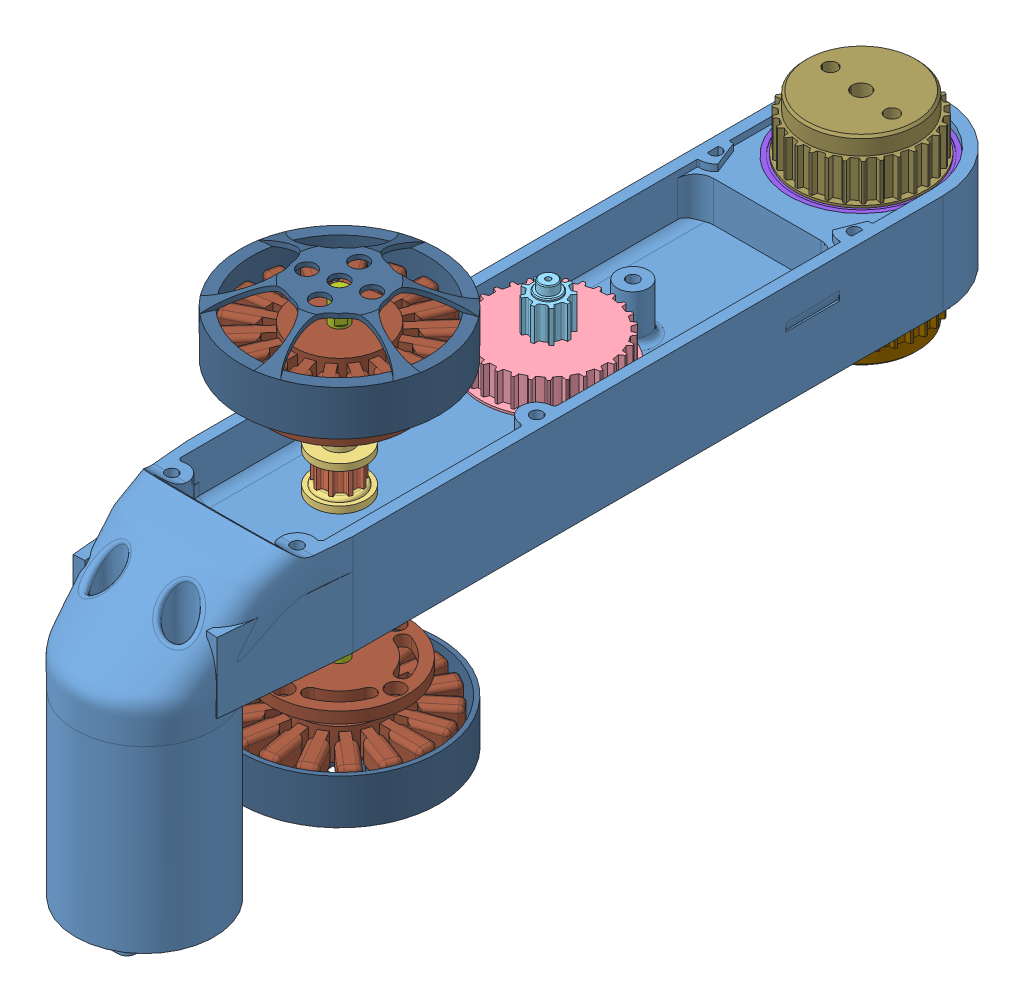
SolidWorks assembly act_core_v3_only body, configuration Default. Lengths in mm.
Overall size (62.68 103.74 194.04).
24 component instances, 12 part files, 56 mates.
Components (placement in the parent):
- upper leg module shell base_v3-1: upper leg module shell base_v3 [Default] at (27.0686 103.6753 170.704) x (-1 0 0) z (0 0 -1) size (37.45 78.01 194.01)
- motor assembly-1: motor assembly [Default] at (27.0686 129.5753 226.2245) x (0.534678 0 -0.845056) z (0.845056 0 0.534678) size (16.67 11.86 16.67)
  - motor pulley-1: motor pulley [Default] at (0 -20.1 0) x (1 0 0) z (0 -1 0) size (8.98 9.1 6.7)
  - encoder wheel mount-1: encoder wheel mount [Default] at (0 -28.3 0) x (-0.562764 0 0.826618) z (-0.826618 0 -0.562764) size (12 5.96 12) (hidden)
- centre pulley-1: centre pulley [Default] at (39.24 91.3287 156.2358) x (0.712464 0 0.701709) z (-0.701709 0 0.712464) size (30 19 30)
  - transmission pulley centre-1: transmission pulley centre [Default] at (7.726 11.8465 25.1899) size (30 6.8 30)
  - centre pulley-1: centre pulley [Default] at (7.726 25.3465 25.1899) x (0.694658 0 -0.71934) z (0 -1 0) size (8.98 9.1 19)
- bearing 8mm x 3mm x 3mm-1: bearing 8mm x 3mm x 3mm [Default] at (27.0686 102.1753 179.604) x (0.990426 0 -0.138045) z (0 -1 0) size (7.96 7.96 3)
- motor shaft_v3-1: motor shaft_v3 [Default] at (27.0686 140.6753 226.2245) x (0.606053 0 -0.795424) z (0 -1 0) size (3.99 3.99 38)
- encoder wheel mount-1: encoder wheel mount [Default] at (27.0686 110.9753 226.2245) x (1 0 0) z (0 0 -1) size (12 5.96 12)
- bearing 32x25x4mm-1: bearing 32x25x4mm [Default] at (27.0686 104.1753 109.704) x (0.998143 0 0.060919) z (-0.060919 0 0.998143) size (32 4 32)
- centre pulley-2: centre pulley [Default] at (27.0686 93.6753 179.604) x (-0.512258 0 -0.858832) z (0 -1 0) size (8.98 9.1 19)
- transmission pulley centre-1: transmission pulley centre [Default] at (27.0686 93.1753 179.604) x (0.289271 0 0.957247) z (0.957247 0 -0.289271) size (30 6.8 30)
- motor pulley-1: motor pulley [Default] at (27.0686 93.6753 226.2245) x (0.534678 0 -0.845056) z (0 -1 0) size (8.98 9.1 6.7)
- encoder wheel mount-2: encoder wheel mount [Default] at (27.0686 84.6753 226.2245) x (0.036347 0 0.999339) z (-0.999339 0 0.036347) size (12 5.96 12)
- transmission pulley output-2: transmission pulley output [Default] at (27.0686 88.1753 109.704) x (0.336451 0 0.941701) z (0.941701 0 -0.336451) size (29 16.4 29)
- motor stator-1: motor stator [Default] at (27.0686 61.9826 226.2245) x (0.681591 0 0.731733) z (0 -1 0) size (44.35 44.35 16.24)
- motor rotor-1: motor rotor [Default] at (27.0686 61.9826 226.2245) x (1 0 0) z (0 0 -1) size (40 13.5 39.72)
- bearing 32x25x4mm-2: bearing 32x25x4mm [Default] at (27.0686 88.6753 109.704) x (0.98877 0 0.149448) z (-0.149448 0 0.98877) size (32 4 32)
- bearing 8mm x 3mm x 3mm-3: bearing 8mm x 3mm x 3mm [Default] at (27.0686 97.1753 179.604) x (0.918615 0 -0.395154) z (0 -1 0) size (7.96 7.96 3)
- motor shaft_v3-2: motor shaft_v3 [Default] at (27.0686 55.6753 226.2245) x (1 0 0) z (0 1 0) size (3.99 3.99 38)
- transmission pulley output_wheel-1: transmission pulley output_wheel [Default] at (27.0686 108.6753 109.704) x (0.991072 0 0.133328) z (-0.133328 0 0.991072) size (29 16.4 29)
- motor stator-2: motor stator [Default] at (27.0686 127.1753 226.2245) x (-0.970824 0 0.239792) z (0 1 0) size (44.35 44.35 16.24)
- motor rotor-2: motor rotor [Default] at (27.0686 128.1753 226.2245) x (-0.84562 0 -0.533785) z (0.533785 0 -0.84562) size (40 13.5 39.72)
Mates (geometry in assembly coordinates):
- Coincident1: coincident aligned: plane of upper leg module shell base_v3-1 through (45.5686 97.6753 130.704) normal (1 0 0); plane of upper leg module cover_v2_2-1 through (45.5686 117.6753 241.7032) normal (1 0 0)
- Coincident2: coincident anti-aligned: plane of upper leg module shell base_v3-1 through (8.5686 109.6753 130.704) normal (0 1 0); plane of upper leg module cover_v2_2-1 through (27.0686 109.6753 164.3332) normal (0 -1 0)
- Concentric1: concentric aligned: cylinder of upper leg module shell base_v3-1 through (27.0686 96.8953 109.704) axis (0 -1 0) radius 18.5018; cylinder of upper leg module cover_v2_2-1 through (27.0686 125.6853 109.704) axis (0 -1 0) radius 18.5018
- Coincident3: coincident anti-aligned: plane of upper leg module shell base_v3-1 through (27.0686 87.1753 109.704) normal (0 -1 0); plane of upper leg module cover_v2_2-2 through (27.0686 87.1753 164.3332) normal (0 1 0)
- Coincident5: coincident aligned: plane of upper leg module shell base_v3-1 through (45.5686 97.6753 130.704) normal (1 0 0); plane of upper leg module cover_v2_2-2 through (45.5686 79.1753 241.7032) normal (1 0 0)
- Concentric6: concentric anti-aligned: cylinder of upper leg module shell base_v3-1 through (27.0686 101.1753 179.604) axis (0 -1 0) radius 3.98; cylinder of centre pulley-1/centre pulley-1 through (27.0686 100.1753 179.604) axis (0 1 0) radius 1.995
- Concentric7: concentric anti-aligned: cylinder of upper leg module shell base_v3-1 through (27.0686 101.1753 179.604) axis (0 -1 0) radius 3.98; cylinder of bearing 8mm x 3mm x 3mm-1 through (27.0686 99.1753 179.604) axis (0 1 0) radius 3.98
- Coincident12: coincident anti-aligned: plane of upper leg module shell base_v3-1 through (13.5686 99.1753 130.704) normal (0 1 0); plane of bearing 8mm x 3mm x 3mm-1 through (27.0686 99.1753 179.604) normal (0 -1 0)
- Coincident15: coincident anti-aligned: plane of centre pulley-1/centre pulley-1 through (27.0686 102.1753 179.604) normal (0 -1 0); plane of bearing 8mm x 3mm x 3mm-1 through (27.0686 102.1753 179.604) normal (0 1 0)
- Coincident16: coincident aligned: plane of motor assembly-1/motor pulley-1 through (27.0686 109.4753 226.2245) normal (0 1 0); plane of centre pulley-1/transmission pulley centre-1 through (27.0686 109.4753 179.604) normal (0 1 0)
- Coincident17: coincident aligned: plane of centre pulley-1/transmission pulley centre-1 through (27.0686 102.6753 179.604) normal (0 -1 0); plane of motor shaft_v3-1 through (27.0686 102.6753 226.2245) normal (0 -1 0)
- Concentric9: concentric aligned: cylinder of motor assembly-1/motor pulley-1 through (27.0686 102.7753 226.2245) axis (0 1 0) radius 2; cylinder of motor shaft_v3-1 through (27.0686 102.6753 226.2245) axis (0 1 0) radius 1.995
- Parallel1: parallel aligned: plane of motor assembly-1/motor pulley-1 through (27.0686 102.7753 226.2245) normal (0 -1 0); plane of motor shaft_v3-1 through (27.0686 102.6753 226.2245) normal (0 -1 0)
- Concentric10: concentric aligned: cylinder of motor shaft_v3-1 through (27.0686 102.6753 226.2245) axis (0 1 0) radius 1.995; cylinder of encoder wheel mount-1 through (27.0686 106.9753 226.2245) axis (0 1 0) radius 2
- Coincident19: coincident anti-aligned: plane of motor assembly-1/motor pulley-1 through (27.0686 109.4753 226.2245) normal (0 1 0); plane of encoder wheel mount-1 through (27.0686 109.4753 226.2245) normal (0 -1 0)
- Concentric11: concentric anti-aligned: cylinder of upper leg module shell base_v3-1 through (27.0686 104.1753 109.704) axis (0 1 0) radius 16; cylinder of bearing 32x25x4mm-1 through (27.0686 108.1753 109.704) axis (0 -1 0) radius 12.5
- Coincident20: coincident anti-aligned: plane of upper leg module shell base_v3-1 through (27.0686 104.1753 109.704) normal (0 1 0); plane of bearing 32x25x4mm-1 through (27.0686 104.1753 109.704) normal (0 -1 0)
- Concentric12: concentric anti-aligned: cylinder of bearing 32x25x4mm-1 through (27.0686 108.1753 109.704) axis (0 -1 0) radius 12.5; cylinder of transmission pulley output-1 through (27.0686 104.3253 109.704) axis (0 1 0) radius 12.575
- Coincident21: coincident anti-aligned: plane of bearing 32x25x4mm-1 through (27.0686 108.1753 109.704) normal (0 1 0); plane of transmission pulley output-1 through (27.0686 108.1753 109.704) normal (0 -1 0)
- Concentric14: concentric anti-aligned: cylinder of upper leg module shell base_v3-1 through (27.0686 88.8753 109.704) axis (0 1 0) radius 16.5; cylinder of bearing 32x25x4mm-2 through (27.0686 92.6753 109.704) axis (0 -1 0) radius 16
- Coincident22: coincident anti-aligned: plane of upper leg module shell base_v3-1 through (27.0686 92.6753 109.704) normal (0 -1 0); circle of bearing 32x25x4mm-2
- Concentric16: concentric aligned: cylinder of transmission pulley output-2 through (27.0686 92.5253 109.704) axis (0 -1 0) radius 12.575; cylinder of bearing 32x25x4mm-2 through (27.0686 92.6753 109.704) axis (0 -1 0) radius 12.5
- Coincident23: coincident anti-aligned: plane of transmission pulley output-2 through (27.0686 88.6753 109.704) normal (0 1 0); plane of bearing 32x25x4mm-2 through (27.0686 88.6753 109.704) normal (0 -1 0)
- Concentric17: concentric aligned: cylinder of upper leg module shell base_v3-1 through (27.0686 96.1753 179.604) axis (0 1 0) radius 3.98; cylinder of bearing 8mm x 3mm x 3mm-3 through (27.0686 94.1753 179.604) axis (0 1 0) radius 3.98
- Coincident25: coincident anti-aligned: plane of upper leg module shell base_v3-1 through (27.0686 97.1753 179.604) normal (0 -1 0); plane of bearing 8mm x 3mm x 3mm-3 through (27.0686 97.1753 179.604) normal (0 1 0)
- Concentric18: concentric anti-aligned: cylinder of centre pulley-2 through (27.0686 96.1753 179.604) axis (0 -1 0) radius 1.995; cylinder of bearing 8mm x 3mm x 3mm-3 through (27.0686 94.1753 179.604) axis (0 1 0) radius 2
- Coincident26: coincident anti-aligned: plane of centre pulley-2 through (27.0686 94.1753 179.604) normal (0 1 0); plane of bearing 8mm x 3mm x 3mm-3 through (27.0686 94.1753 179.604) normal (0 -1 0)
- Coincident27: coincident aligned: plane of centre pulley-2 through (27.0686 93.6753 179.604) normal (0 1 0); plane of transmission pulley centre-1 through (27.0686 93.6753 179.604) normal (0 1 0)
- Concentric19: concentric aligned: circle of centre pulley-2; cylinder of transmission pulley centre-1 through (27.0686 93.6753 179.604) axis (0 -1 0) radius 15
- Coincident28: coincident aligned: cylinder of centre pulley-2 through (27.0686 79.6753 179.604) axis (0 1 0) radius 4.57; circle of transmission pulley centre-1
- Parallel2: parallel anti-aligned: plane of transmission pulley centre-1 through (27.2454 96.8753 175.7377) normal (0.969507 0 0.245065); plane of centre pulley-2 through (26.3162 79.6753 179.4139) normal (-0.969507 0 -0.245065)
- Coincident30: coincident anti-aligned: plane of upper leg module cover_v2_2-2 through (27.0686 79.1753 164.3332) normal (0 -1 0); plane of motor rotor-1 through (27.0686 69.4826 226.2245) normal (0 1 0)
- Concentric20: concentric aligned: cylinder of upper leg module cover_v2_2-2 through (14.5686 84.1753 223.504) axis (0 -1 0) radius 1.6; cylinder of motor rotor-1 through (14.5686 69.4826 226.2245) axis (0 -1 0) radius 2
- Concentric21: concentric aligned: line of motor stator-1 through (27.0686 51.9826 226.2245) axis (0 1 0); axis of motor rotor-1 through (27.0686 55.9826 226.2245) axis (0 1 0)
- Concentric22: concentric aligned: cylinder of upper leg module cover_v2_2-2 through (27.0686 84.1753 223.504) axis (0 -1 0) radius 12.5; cylinder of motor rotor-1 through (27.0686 69.4826 226.2245) axis (0 -1 0) radius 15
- Coincident33: coincident aligned: plane of motor stator-1 through (27.0686 61.9826 226.2245) normal (0 1 0); plane of motor rotor-1 through (27.0686 61.9826 226.2245) normal (0 1 0)
- Concentric23: concentric anti-aligned: cylinder of motor rotor-1 through (27.0686 56.9826 226.2245) axis (0 1 0) radius 2; cylinder of motor shaft_v3-2 through (27.0686 93.6753 226.2245) axis (0 -1 0) radius 1.995
- Coincident34: coincident aligned: plane of transmission pulley centre-1 through (27.0686 93.6753 179.604) normal (0 1 0); plane of motor shaft_v3-2 through (27.0686 93.6753 226.2245) normal (0 1 0)
- Concentric24: concentric anti-aligned: cylinder of motor pulley-1 through (27.0686 86.9753 226.2245) axis (0 1 0) radius 2; line of motor shaft_v3-2 through (27.0686 93.4753 226.2245) axis (0 -1 0)
- Coincident35: coincident aligned: plane of transmission pulley centre-1 through (27.0686 93.6753 179.604) normal (0 1 0); plane of motor pulley-1 through (27.0686 93.6753 226.2245) normal (0 1 0)
- Concentric25: concentric aligned: line of upper leg module cover_v2_2-2 through (27.0686 83.1753 223.504) axis (0 -1 0); cylinder of encoder wheel mount-2 through (27.0686 88.6753 223.504) axis (0 -1 0) radius 2
- Coincident36: coincident anti-aligned: plane of motor pulley-1 through (27.0686 86.9753 226.2245) normal (0 -1 0); plane of encoder wheel mount-2 through (27.0686 86.9753 226.2245) normal (0 1 0)
- Concentric26: concentric anti-aligned: cylinder of bearing 32x25x4mm-1 through (27.0686 108.1753 109.704) axis (0 -1 0) radius 12.5; cylinder of transmission pulley output_wheel-1 through (27.0686 104.3253 109.704) axis (0 1 0) radius 12.575
- Coincident37: coincident anti-aligned: plane of bearing 32x25x4mm-1 through (27.0686 108.1753 109.704) normal (0 1 0); plane of transmission pulley output_wheel-1 through (27.0686 108.1753 109.704) normal (0 -1 0)
- Concentric27: concentric aligned: cylinder of motor shaft_v3-3 through (27.0686 153.0074 109.704) axis (0 -1 0) radius 1.995; cylinder of transmission pulley output_wheel-1 through (27.0686 143.4713 109.704) axis (0 -1 0) radius 1.995
- Coincident38: coincident anti-aligned: plane of transmission pulley output-2 through (37.2261 92.5253 111.3845) normal (-0.336451 0 -0.941701); plane of lower leg-1 through (21.6881 81.1653 116.9359) normal (0.336451 0 0.941701)
- Coincident39: coincident anti-aligned: plane of transmission pulley output-2 through (20.2755 92.5253 117.4406) normal (0.941701 0 -0.336451); plane of lower leg-1 through (19.7708 81.1653 116.0281) normal (-0.941701 0 0.336451)
- Coincident40: coincident anti-aligned: plane of upper leg module cover_v2_2-2 through (27.0686 71.1653 109.704) normal (0 -1 0); plane of lower leg-1 through (167.4344 71.1653 71.2351) normal (0 1 0)
- Concentric29: concentric anti-aligned: line of motor shaft_v3-1 through (27.0686 102.8753 226.2245) axis (0 1 0); cylinder of motor shaft_v3-2 through (27.0686 93.6753 226.2245) axis (0 -1 0) radius 1.995
- Concentric30: concentric anti-aligned: cylinder of encoder wheel mount-2 through (27.0686 81.0153 226.2245) axis (0 1 0) radius 3; cylinder of motor shaft_v3-2 through (27.0686 93.6753 226.2245) axis (0 -1 0) radius 1.995
- Distance1: distance = 13.8073 mm anti-aligned: plane of motor rotor-1 through (27.0686 69.4826 226.2245) normal (0 1 0); plane of motor shaft_v3-2 through (27.0686 55.6753 226.2245) normal (0 -1 0)
- Concentric32: concentric anti-aligned: cylinder of motor shaft_v3-1 through (27.0686 102.6753 226.2245) axis (0 1 0) radius 1.995; cylinder of motor rotor-2 through (27.0686 133.1753 226.2245) axis (0 -1 0) radius 2
- Concentric33: concentric aligned: cylinder of upper leg module shell base_v3-1 through (27.0686 89.1753 226.2245) axis (0 1 0) radius 2; line of motor shaft_v3-1 through (27.0686 102.8753 226.2245) axis (0 1 0)
- Distance3: distance = 20 mm anti-aligned: plane of motor rotor-2 through (27.0686 120.6753 226.2245) normal (0 -1 0); plane of motor shaft_v3-1 through (27.0686 140.6753 226.2245) normal (0 1 0)
- Concentric34: concentric aligned: cylinder of motor shaft_v3-1 through (27.0686 102.6753 226.2245) axis (0 1 0) radius 1.995; cylinder of motor stator-2 through (27.0686 140.1753 226.2245) axis (0 1 0) radius 2
- Distance4: distance = 1 mm aligned: plane of motor stator-2 through (27.0686 127.1753 226.2245) normal (0 -1 0); plane of motor rotor-2 through (27.0686 128.1753 226.2245) normal (0 -1 0)
